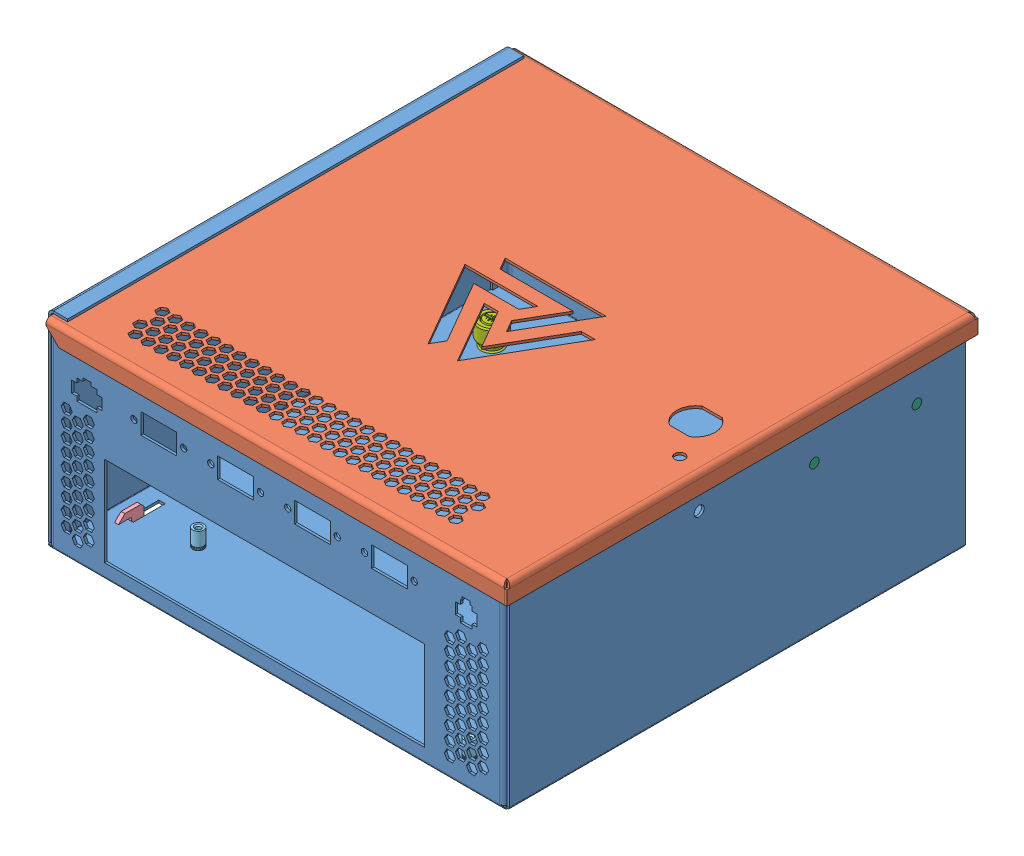
SolidWorks assembly CPU Box, configuration Default. Lengths in mm.
Overall size (231.03 108.19 233.57).
12 component instances, 8 part files, 26 mates.
Components (placement in the parent):
- Enclosure_Base-1: Enclosure_Base [Default] at (-155.6186 -50.875 116.6815) size (228.6 101.54 228.6)
- Enclosure_Lid-1: Enclosure_Lid [Default] at (-153.1345 49.3992 116.6815) x (0 0 -1) z (-1 0 0) size (233.57 9.53 228.55)
- Cherry_Bracket_2-1: Cherry_Bracket_2 [Default] at (71.7673 13.26 -92.8685) x (0 0 1) z (-1 0 0) size (63.5 26.61 26.61)
- Mount Up-1: Mount Up [Default] at (60.2814 -55.6248 -88.4794) x (-1 0 0) z (0 0 -1) size (208.9 12.7 180.97)
- 375 standoff BSO-632-12ZI-1: 375 standoff BSO-632-12ZI [Default] at (40.9955 -50.24 103.1992) x (0 -1 0) z (0 0 1) size (9.53 6.35 7.33)
- 375 standoff BSO-632-12ZI-2: 375 standoff BSO-632-12ZI [Default] at (40.9955 -50.24 -51.7408) x (0 -1 0) z (-0.547319 0 0.836924) size (9.53 6.35 7.33)
- 375 standoff BSO-632-12ZI-3: 375 standoff BSO-632-12ZI [Default] at (-116.4845 -50.24 80.3392) x (0 -1 0) z (0 0 1) size (9.53 6.35 7.33)
- 375 standoff BSO-632-12ZI-4: 375 standoff BSO-632-12ZI [Default] at (-116.4845 -50.24 -51.7408) x (0 -1 0) z (0 0 1) size (9.53 6.35 7.33)
- Cherry stud FH-632-6ZI-1: Cherry stud FH-632-6ZI [Default] at (72.9814 22.785 -86.5185) x (-1 0 0) z (0 -0.924225 -0.381849) size (9.53 5.23 5.23)
- Cherry stud FH-632-6ZI-2: Cherry stud FH-632-6ZI [Default] at (72.9814 22.785 -35.7185) x (-1 0 0) z (0 -0.924225 -0.381849) size (9.53 5.23 5.23)
- Thumbscrew PF11-832-0-1: Thumbscrew PF11-832-0 [Default] at (-130.2186 -49.6608 -78.9544) x (1 0 0) z (0 1 0) size (13.06 13.06 17.27)
- Thumbscrew standoff CSS-832-3-1: Thumbscrew standoff CSS-832-3 [Default] at (-130.2186 -55.6248 -78.9544) x (0 1 0) z (0.963598 0 0.267356) size (5.8 8.74 9.17)
Mates (geometry in assembly coordinates):
- Coincident1: coincident anti-aligned: plane of Enclosure_Base-1 through (-155.6186 48.185 116.6815) normal (0 1 0); plane of Enclosure_Lid-1 through (72.9255 48.185 116.6815) normal (0 -1 0)
- Coincident2: coincident aligned: line of Enclosure_Base-1 through (-151.9185 48.185 -111.9185) axis (1 0 0); line of Enclosure_Lid-1 through (-153.1345 48.185 -111.9185) axis (1 0 0)
- Coincident3: coincident: line of Enclosure_Base-1 through (-153.1345 49.455 -110.7026) axis (0 0 1); plane of Enclosure_Lid-1 through (-153.1345 48.185 116.6815) normal (-1 0 0)
- Coincident6: coincident anti-aligned: plane of Enclosure_Base-1 through (71.7673 48.185 116.6815) normal (-1 0 0); plane of Cherry_Bracket_2-1 through (71.7673 38.66 -92.8685) normal (1 0 0)
- Coincident14: coincident anti-aligned: plane of Enclosure_Base-1 through (-142.9186 -50.875 86.1456) normal (0 0 -1); plane of Mount Up-1 through (63.1313 -50.5448 86.1456) normal (0 0 1)
- Coincident15: coincident: plane of Enclosure_Base-1 through (-155.6186 -49.6608 -111.9185) normal (0 1 0); plane of Mount Up-1 through (63.1313 -48.0048 92.4956) normal (0 -1 0)
- Concentric12: concentric aligned: cylinder of Enclosure_Base-1 through (71.7673 22.785 -35.7185) axis (1 0 0) radius 1.7399; cylinder of Cherry_Bracket_2-1 through (70.5532 22.785 -35.7185) axis (1 0 0) radius 2.0638
- Concentric13: concentric aligned: cylinder of Enclosure_Base-1 through (71.7673 22.785 -86.5185) axis (1 0 0) radius 1.7399; cylinder of Cherry_Bracket_2-1 through (70.5532 22.785 -86.5185) axis (1 0 0) radius 2.0638
- Concentric14: concentric anti-aligned: cylinder of Enclosure_Base-1 through (-116.4845 -50.875 80.3392) axis (0 1 0) radius 2.7051; cylinder of 375 standoff BSO-632-12ZI-3 through (-116.4845 -45.4775 80.3392) axis (0 -1 0) radius 2.6924
- Coincident16: coincident aligned: plane of 375 standoff BSO-632-12ZI-3 through (-116.4845 -50.875 80.3392) normal (0 -1 0); plane of Enclosure_Base-1 through (-155.6186 -50.875 -111.9185) normal (0 -1 0)
- Concentric15: concentric anti-aligned: cylinder of Enclosure_Base-1 through (40.9955 -50.875 103.1992) axis (0 1 0) radius 2.7051; cylinder of 375 standoff BSO-632-12ZI-1 through (40.9955 -45.4775 103.1992) axis (0 -1 0) radius 2.6924
- Coincident17: coincident aligned: plane of 375 standoff BSO-632-12ZI-1 through (40.9955 -50.875 103.1992) normal (0 -1 0); plane of Enclosure_Base-1 through (-155.6186 -50.875 -111.9185) normal (0 -1 0)
- Concentric16: concentric anti-aligned: cylinder of Enclosure_Base-1 through (40.9955 -50.875 -51.7408) axis (0 1 0) radius 2.7051; cylinder of 375 standoff BSO-632-12ZI-2 through (40.9955 -45.4775 -51.7408) axis (0 -1 0) radius 2.6924
- Coincident18: coincident aligned: plane of 375 standoff BSO-632-12ZI-2 through (40.9955 -50.875 -51.7408) normal (0 -1 0); plane of Enclosure_Base-1 through (-155.6186 -50.875 -111.9185) normal (0 -1 0)
- Concentric19: concentric anti-aligned: cylinder of Enclosure_Base-1 through (-116.4845 -50.875 -51.7408) axis (0 1 0) radius 2.7051; cylinder of 375 standoff BSO-632-12ZI-4 through (-116.4845 -45.4775 -51.7408) axis (0 -1 0) radius 2.6924
- Coincident20: coincident aligned: plane of 375 standoff BSO-632-12ZI-4 through (-116.4845 -50.875 -51.7408) normal (0 -1 0); plane of Enclosure_Base-1 through (-155.6186 -50.875 -111.9185) normal (0 -1 0)
- Concentric20: concentric aligned: cylinder of Enclosure_Base-1 through (71.7673 22.785 -35.7185) axis (1 0 0) radius 1.7399; cylinder of Cherry stud FH-632-6ZI-2 through (68.1935 22.785 -35.7185) axis (1 0 0) radius 1.7526
- Coincident21: coincident aligned: plane of Cherry stud FH-632-6ZI-2 through (72.9814 21.697 -36.1681) normal (1 0 0); plane of Enclosure_Base-1 through (72.9814 48.185 116.6815) normal (1 0 0)
- Concentric21: concentric aligned: cylinder of Enclosure_Base-1 through (71.7673 22.785 -86.5185) axis (1 0 0) radius 1.7399; cylinder of Cherry stud FH-632-6ZI-1 through (68.1935 22.785 -86.5185) axis (1 0 0) radius 1.7526
- Coincident22: coincident aligned: plane of Cherry stud FH-632-6ZI-1 through (72.9814 21.697 -86.9681) normal (1 0 0); plane of Enclosure_Base-1 through (72.9814 48.185 116.6815) normal (1 0 0)
- Concentric22: concentric aligned: cylinder of Enclosure_Base-1 through (-130.2186 -50.875 -78.9544) axis (0 1 0) radius 3.9624; cylinder of Mount Up-1 through (-130.2186 -57.5221 -78.9544) axis (0 1 0) radius 3.9624
- Concentric23: concentric anti-aligned: cylinder of Mount Up-1 through (-130.2186 -57.5221 -78.9544) axis (0 1 0) radius 3.9624; cylinder of Thumbscrew standoff CSS-832-3-1 through (-130.2186 -53.2846 -78.9544) axis (0 -1 0) radius 3.1115
- Coincident24: coincident aligned: plane of Mount Up-1 through (60.2814 -55.6248 -88.4794) normal (0 1 0); plane of Thumbscrew standoff CSS-832-3-1 through (-130.8318 -55.6248 -76.7443) normal (0 1 0)
- Concentric24: concentric anti-aligned: cylinder of Enclosure_Base-1 through (-130.2186 -50.875 -78.9544) axis (0 1 0) radius 3.9624; cylinder of Thumbscrew PF11-832-0-1 through (-130.2186 -52.3456 -78.9544) axis (0 -1 0) radius 2.0828
- Coincident25: coincident anti-aligned: plane of Enclosure_Base-1 through (-155.6186 -49.6608 -111.9185) normal (0 1 0); plane of Thumbscrew PF11-832-0-1 through (-125.3227 -49.6608 -78.9544) normal (0 -1 0)
- Coincident28: coincident anti-aligned: plane of Enclosure_Base-1 through (-155.6186 -50.875 -111.9185) normal (0 -1 0); plane of Thumbscrew standoff CSS-832-3-1 through (-128.7529 -50.875 -78.5477) normal (0 1 0)
